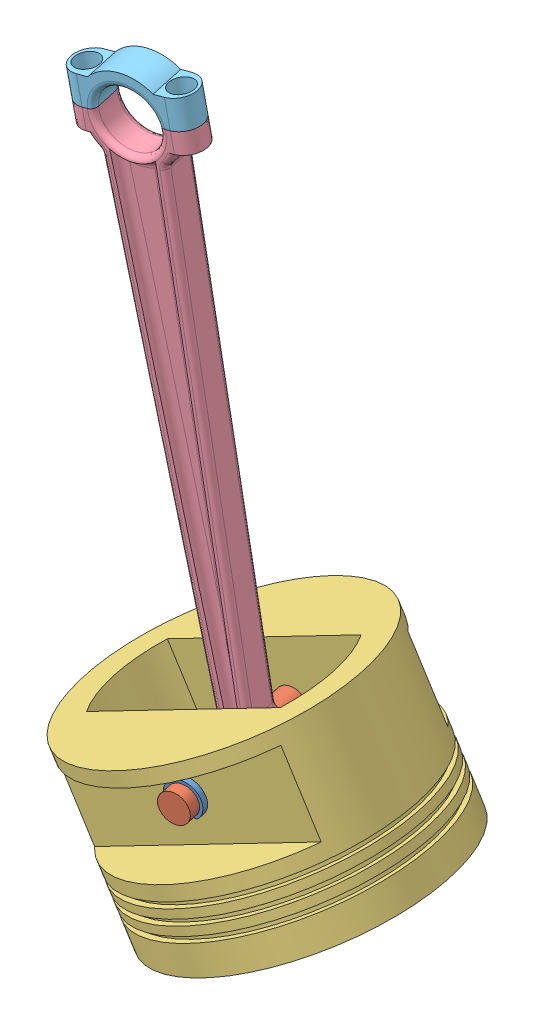
SolidWorks assembly piston, configuration Default. Lengths in mm.
Overall size (124.66 262.73 112.46).
8 component instances, 5 part files, 18 mates.
Components (placement in the parent):
- C clip 6mm inner, 12mm outer-1: C clip 6mm inner, 12mm outer [Default] at (-54.593 75.297 36.5632) x (0.984863 0.004767 -0.173271) z (0.004519 0.998576 0.053159) size (12 2 10.86)
- conrod-1: conrod [Default] at (-50.1744 73.942 61.6409) x (-0.720039 -0.688113 0.089688) z (0.173277 -0.053137 0.983439) size (10 10 67)
- piston head-1: piston head [Default] at (-40.0688 38.2448 23.8674) x (0.173277 -0.053137 0.983439) z (0.905199 0.402038 -0.137769) size (94 60 94)
- C clip 6mm inner, 12mm outer-2: C clip 6mm inner, 12mm outer [Default] at (-57.0189 76.0409 22.795) x (0.223524 0.974608 0.013276) z (-0.959173 0.217522 0.180755) size (12 2 10.86)
- C clip 6mm inner, 12mm outer-3: C clip 6mm inner, 12mm outer [Default] at (-60.7444 77.1834 1.6511) x (0.97149 0.173277 -0.16181) z (-0.16181 0.983439 0.081647) size (12 2 10.86)
- C clip 6mm inner, 12mm outer-4: C clip 6mm inner, 12mm outer [Default] at (-50.8675 74.1546 57.7071) x (0.97149 0.173277 -0.16181) z (-0.16181 0.983439 0.081647) size (12 2 10.86)
- piston rod-2: piston rod [Default] at (-54.9396 75.4033 34.5963) x (0.976273 0.140936 -0.1644) z (-0.129866 0.988592 0.076297) size (39.11 12.84 199.57)
- pistoncaps-2: pistoncaps [Default] at (-55.3421 78.4679 34.8328) x (0.976273 0.140936 -0.1644) z (-0.129866 0.988592 0.076297) size (39.11 12.23 13.87)
Mates (geometry in assembly coordinates):
- Coincident1: coincident anti-aligned: plane of C clip 6mm inner, 12mm outer-1 through (-54.9396 75.4033 34.5963) normal (-0.173277 0.053137 -0.983439); plane of conrod-1 through (-54.9396 75.4033 34.5963) normal (0.173277 -0.053137 0.983439)
- Concentric2: concentric anti-aligned: cylinder of C clip 6mm inner, 12mm outer-1 through (-54.9396 75.4033 34.5963) axis (0.173277 -0.053137 0.983439) radius 3; cylinder of conrod-1 through (-61.784 77.5022 -4.2495) axis (-0.173277 0.053137 -0.983439) radius 5
- Coincident3: coincident: plane of ? through (-98.8386 147.094 34.0026) normal (-0.502612 0.853954 0.134699); plane of ? through (-98.8386 147.094 34.0026) normal (0.502612 -0.853954 -0.134699)
- Coincident4: coincident anti-aligned: circle of conrod-1; plane of piston head-1 through (-77.8481 17.8878 57.3871) normal (0.173277 -0.053137 0.983439)
- Coincident5: coincident anti-aligned: circle of C clip 6mm inner, 12mm outer-1; plane of ? through (-185.0223 182.5253 63.3043) normal (0.173277 -0.053137 0.983439)
- Coincident6: coincident aligned: circle of conrod-1; plane of C clip 6mm inner, 12mm outer-3 through (-61.0909 77.2897 -0.3158) normal (-0.173277 0.053137 -0.983439)
- Coincident8: coincident anti-aligned: plane of conrod-1 through (-51.2141 74.2608 55.7402) normal (0.173277 -0.053137 0.983439); plane of C clip 6mm inner, 12mm outer-4 through (-51.2141 74.2608 55.7402) normal (-0.173277 0.053137 -0.983439)
- Concentric6: concentric anti-aligned: cylinder of conrod-1 through (-61.784 77.5022 -4.2495) axis (-0.173277 0.053137 -0.983439) radius 5; cylinder of C clip 6mm inner, 12mm outer-4 through (-51.2141 74.2608 55.7402) axis (0.173277 -0.053137 0.983439) radius 3
- Concentric7: concentric aligned: circle of conrod-1; circle of C clip 6mm inner, 12mm outer-2
- Coincident9: coincident aligned: cylinder of conrod-1 through (-61.784 77.5022 -4.2495) axis (-0.173277 0.053137 -0.983439) radius 3; circle of C clip 6mm inner, 12mm outer-3
- Coincident10: coincident: circle of ?; cylinder of ? through (-92.6336 167.3489 40.1048) axis (0.502612 -0.853954 -0.134699) radius 3
- Concentric8: concentric anti-aligned: cylinder of conrod-1 through (-61.784 77.5022 -4.2495) axis (-0.173277 0.053137 -0.983439) radius 5; cylinder of piston head-1 through (-64.1233 78.2196 -17.5259) axis (0.173277 -0.053137 0.983439) radius 5
- Coincident11: coincident anti-aligned: plane of conrod-1 through (-57.0189 76.0409 22.795) normal (-0.173277 0.053137 -0.983439); plane of C clip 6mm inner, 12mm outer-2 through (-57.0189 76.0409 22.795) normal (0.173277 -0.053137 0.983439)
- Coincident12: coincident anti-aligned: plane of C clip 6mm inner, 12mm outer-1 through (-54.9396 75.4033 34.5963) normal (-0.173277 0.053137 -0.983439); plane of piston rod-2 through (-54.9396 75.4033 34.5963) normal (0.173277 -0.053137 0.983439)
- Concentric10: concentric aligned: circle of piston rod-2; circle of pistoncaps-2
- Coincident13: coincident anti-aligned: plane of piston rod-2 through (-94.7656 260.7405 45.5266) normal (-0.129866 0.988592 0.076297); plane of pistoncaps-2 through (-106.0727 259.6098 40.931) normal (0.129866 -0.988592 -0.076297)
- Concentric11: concentric aligned: cylinder of piston rod-2 through (-41.4449 67.7469 25.7039) axis (-0.129866 0.988592 0.076297) radius 6; cylinder of pistoncaps-2 through (-41.8475 70.8115 25.9404) axis (-0.129866 0.988592 0.076297) radius 6
- Concentric13: concentric anti-aligned: cylinder of conrod-1 through (-61.784 77.5022 -4.2495) axis (-0.173277 0.053137 -0.983439) radius 5; cylinder of piston rod-2 through (-57.0189 76.0409 22.795) axis (0.173277 -0.053137 0.983439) radius 5
